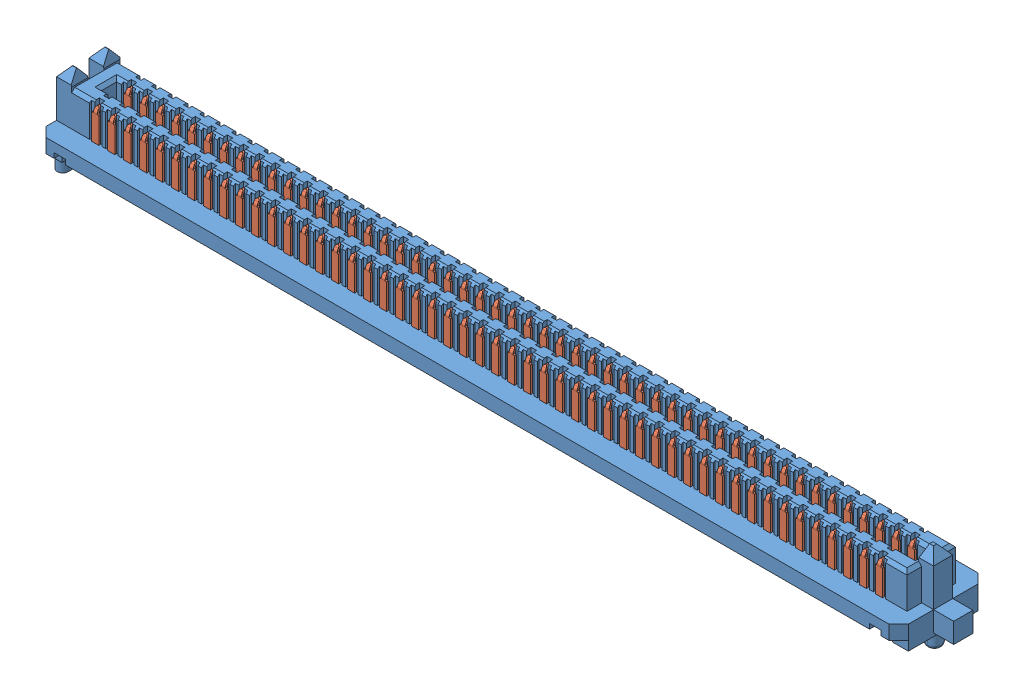
SolidWorks assembly SEAM_50_02_0_L_04_2_A_K_TR, configuration Default. Lengths in mm.
Overall size (70.08 6.88 7.06).
4 component instances, 4 part files, 0 mates.
Components (placement in the parent):
- _SEAM_50_02_0_L_04_1_A_K_TR_body_2-1: _SEAM_50_02_0_L_04_1_A_K_TR_body_2 [Default] at origin size (70.08 6.88 7.06)
- _SEAM_50_02_0_L_04_1_A_K_TR_conn_4-1: _SEAM_50_02_0_L_04_1_A_K_TR_conn_4 [Default] at origin size (67.97 4.25 6.55)
- _SEAM_K_Pad_04_6-1: _SEAM_K_Pad_04_6 [Default] at (0 2.7432 0) size (5.99 0.13 5.99) (hidden)
- _SEAM_Triangle_8-1: _SEAM_Triangle_8 [Default] at (32.2834 1.3462 -1.6764) x (-1 0 0) z (0 0 -1) size (1.02 1.27 0.13)
